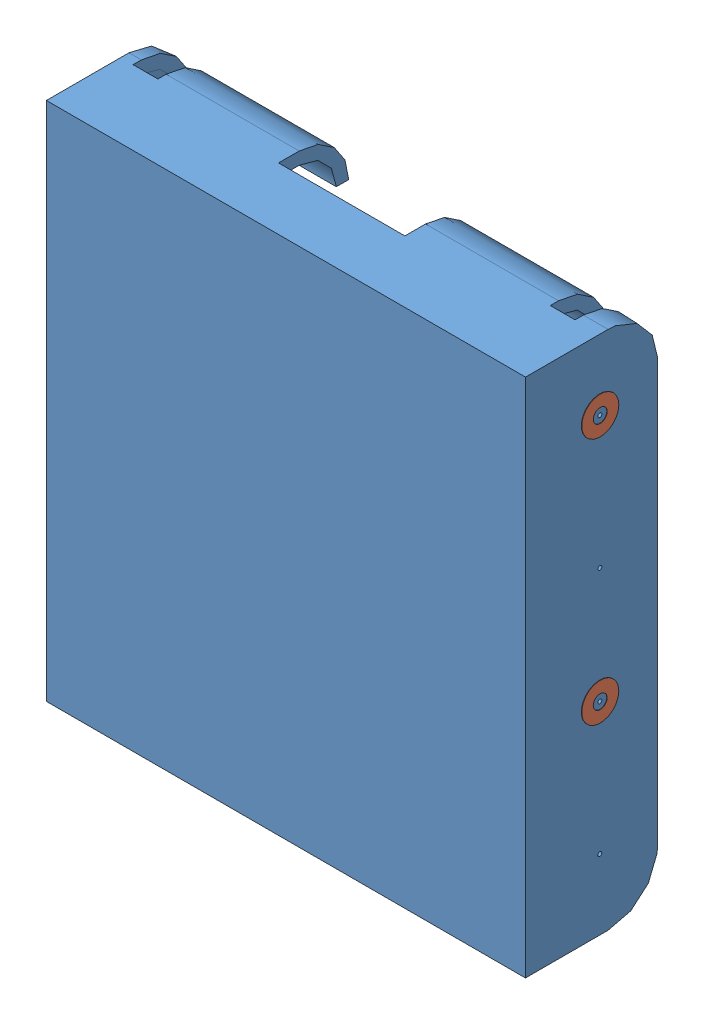
SolidWorks assembly Coupleur 4 piles complet, configuration Défaut. Lengths in mm.
Overall size (58.11 63 16).
9 component instances, 3 part files, 8 mates.
Components (placement in the parent):
- COUPLEUR 4PILES LR6  corps-1: COUPLEUR 4PILES LR6  corps [Défaut] at (-4.3277 -2.6345 0) size (58.01 63 16)
- RESSORT PILE 2-1: RESSORT PILE 2 [Défaut] at (-30.6319 -10.8847 -8.9988) x (0 0.000099 -1) z (1 -0.000099 0) size (7.97 8 2.5)
- RESSORT PILE 2-2: RESSORT PILE 2 [Défaut] at (-30.629 19.1153 -8.9988) x (0 0.000099 -1) z (1 -0.000099 0) size (7.97 8 2.5)
- RESSORT PILE 2-3: RESSORT PILE 2 [Défaut] at (23.4726 35.1157 -9.0012) x (0 0.000099 1) z (-1 0.000099 0) size (7.97 8 2.5)
- RESSORT PILE 2-4: RESSORT PILE 2 [Défaut] at (23.4696 5.1157 -9.0012) x (0 0.000099 1) z (-1 0.000099 0) size (7.97 8 2.5)
- Ressort_contact-2: Ressort_contact [Défaut] at (-31.2555 -6.8789 -9) x (-0.000085 -0.864499 -0.502634) z (1 -0.000099 0) size (4.02 3.91 9.75)
- Ressort_contact-3: Ressort_contact [Défaut] at (-31.2393 23.1211 -9) x (-0.000089 -0.905579 -0.424177) z (1 -0.000099 0) size (4.02 3.91 9.75)
- Ressort_contact-4: Ressort_contact [Défaut] at (24.0539 7.1099 -9) x (0 0.000099 1) z (-1 0.000099 0) size (4.02 3.91 9.75)
- Ressort_contact-5: Ressort_contact [Défaut] at (24.0575 -22.8901 -9) x (-0.000002 -0.015733 0.999876) z (-1 0.000099 0) size (4.02 3.91 9.75)
Mates (geometry in assembly coordinates):
- Coïncidente1: coincident anti-aligned: axis of COUPLEUR 4PILES LR6  corps-1 through (-31.0802 7.1154 -9) axis (-1 0.000099 0); axis of RESSORT PILE 2-2 through (-32.4302 7.1155 -9) axis (1 -0.000099 0)
- Coïncidente2: coincident anti-aligned: axis of COUPLEUR 4PILES LR6  corps-1 through (-31.0831 -22.8846 -9) axis (-1 0.000099 0); axis of RESSORT PILE 2-1 through (-32.4331 -22.8845 -9) axis (1 -0.000099 0)
- Distance2: distance = 0.05 mm aligned: plane of COUPLEUR 4PILES LR6  corps-1 through (-32.5777 31.6155 -16) normal (-1 0.000099 0); plane of RESSORT PILE 2-1 through (-32.6331 -22.8845 -9) normal (-1 0.000099 0)
- Distance3: distance = 0.05 mm aligned: plane of COUPLEUR 4PILES LR6  corps-1 through (-32.5777 31.6155 -16) normal (-1 0.000099 0); plane of RESSORT PILE 2-2 through (-32.6302 7.1155 -9) normal (-1 0.000099 0)
- Coïncidente5: coincident anti-aligned: axis of COUPLEUR 4PILES LR6  corps-1 through (23.9214 23.1157 -9) axis (1 -0.000099 0); axis of RESSORT PILE 2-3 through (25.2714 23.1155 -9) axis (-1 0.000099 0)
- Coïncidente6: coincident anti-aligned: axis of COUPLEUR 4PILES LR6  corps-1 through (23.9185 -6.8843 -9) axis (1 -0.000099 0); axis of RESSORT PILE 2-4 through (25.2685 -6.8845 -9) axis (-1 0.000099 0)
- Distance4: distance = 0.05 mm aligned: plane of COUPLEUR 4PILES LR6  corps-1 through (25.4223 31.6155 -16) normal (1 -0.000099 0); plane of RESSORT PILE 2-4 through (25.4685 -6.8845 -9) normal (1 -0.000099 0)
- Distance5: distance = 0.05 mm aligned: plane of COUPLEUR 4PILES LR6  corps-1 through (25.4223 31.6155 -16) normal (1 -0.000099 0); plane of RESSORT PILE 2-3 through (25.4714 23.1155 -9) normal (1 -0.000099 0)
